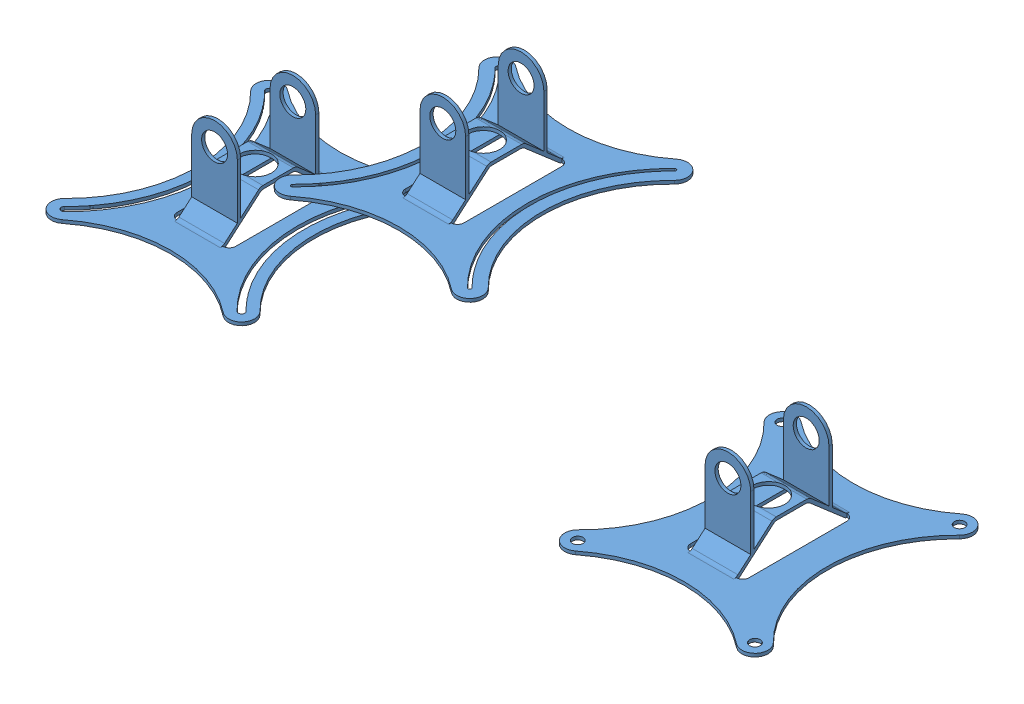
SolidWorks assembly Assem2, configuration Default. Lengths in mm.
Overall size (657.71 233.77 282.29).
3 component instances, 1 part files, 0 mates.
Components (placement in the parent):
- TV_Brackket_1-2: TV_Brackket_1 [_New2] at (44.7002 -258.0792 57.564) size (197.87 91.01 224.69)
- TV_Brackket_1-3: TV_Brackket_1 [_New3] at (-119.9329 -331.3853 115.1632) size (197.87 91.01 224.69)
- TV_Brackket_1-4: TV_Brackket_1 [_New4] at (339.9081 -400.845 75.1694) size (197.87 91.01 224.69)
